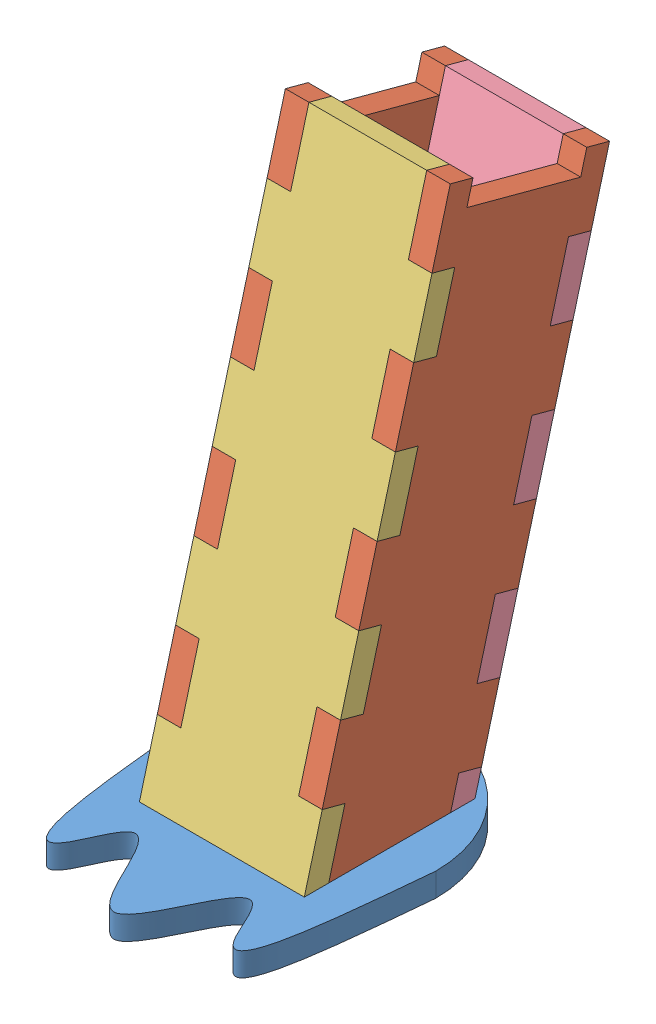
SolidWorks assembly long_leg, configuration Default. Lengths in mm.
Overall size (64 154.05 105.26).
5 component instances, 4 part files, 13 mates.
Components (placement in the parent):
- foot-1: foot [Default] at (14.0978 6 -58.9389) x (1 0 0) z (0 -1 0) size (64 82 6)
- long_leg_right-1: long_leg_right [Default] at (81.114 -18.404 -50.7031) x (0 0.258819 0.965926) z (-1 0 0) size (42 148.23 6)
- long_leg_right-2: long_leg_right [Default] at (45.114 -18.404 -50.7031) x (0 0.258819 0.965926) z (-1 0 0) size (42 148.23 6)
- long_leg_front-1: long_leg_front [Default] at (21.1047 -7.2156 0.7968) x (1 0 0) z (0 0.258819 0.965926) size (42 148.23 6)
- long_leg_back-1: long_leg_back [Default] at (97.9981 -5.6307 -30.6862) x (-1 0 0) z (0 -0.258819 -0.965926) size (42 140.19 6)
Mates (geometry in assembly coordinates):
- Coincident1: coincident anti-aligned: plane of foot-1 through (60.114 0 30.9857) normal (0 -1 0)
- Coincident2: coincident anti-aligned: plane of long_leg_right-2 through (39.114 38.86 -11.5492) normal (0 0.258819 0.965926); plane of long_leg_front-1 through (21.1047 -7.2156 0.7968) normal (0 -0.258819 -0.965926)
- Coincident3: coincident anti-aligned: plane of long_leg_right-2 through (45.114 -18.404 -50.7031) normal (1 0 0); plane of long_leg_front-1 through (45.114 40.4129 -5.7536) normal (-1 0 0)
- Coincident4: coincident anti-aligned: plane of long_leg_right-2 through (39.114 38.86 -11.5492) normal (0 0.965926 -0.258819); plane of long_leg_front-1 through (45.114 40.4129 -5.7536) normal (0 -0.965926 0.258819)
- Coincident5: coincident anti-aligned: plane of long_leg_right-1 through (75.114 0 -1.1367) normal (0 0.258819 0.965926); plane of long_leg_front-1 through (21.1047 -7.2156 0.7968) normal (0 -0.258819 -0.965926)
- Coincident6: coincident anti-aligned: plane of long_leg_right-1 through (75.114 -18.404 -50.7031) normal (-1 0 0); plane of long_leg_front-1 through (75.114 144.7329 -33.7061) normal (1 0 0)
- Coincident7: coincident anti-aligned: plane of long_leg_right-1 through (75.114 127.3463 -29.0473) normal (0 -0.965926 0.258819); plane of long_leg_front-1 through (81.114 127.3463 -29.0473) normal (0 0.965926 -0.258819)
- Coincident8: coincident anti-aligned: plane of long_leg_right-1 through (75.114 13.7088 -35.8682) normal (0 -0.258819 -0.965926); plane of long_leg_back-1 through (97.9981 -5.6307 -30.6862) normal (0 0.258819 0.965926)
- Coincident9: coincident anti-aligned: plane of long_leg_right-1 through (75.114 12.1559 -41.6638) normal (0 -0.965926 0.258819); plane of long_leg_back-1 through (75.114 12.1559 -41.6638) normal (0 0.965926 -0.258819)
- Coincident10: coincident anti-aligned: plane of long_leg_right-1 through (75.114 -18.404 -50.7031) normal (-1 0 0); plane of long_leg_back-1 through (75.114 29.5425 -46.3225) normal (1 0 0)
- Coincident13: coincident anti-aligned: plane of foot-1 through (39.114 0 -58.9389) normal (1 0 0); plane of long_leg_right-2 through (39.114 -18.404 -50.7031) normal (-1 0 0)
- Coincident15: coincident aligned: plane of foot-1 through (60.114 0 30.9857) normal (0 -1 0); plane of long_leg_right-1 through (75.114 0 -32.195) normal (0 -1 0)
- Coincident19: coincident: line of foot-1 through (81.114 6 -40.0143) axis (-1 0 0); plane of long_leg_back-1 through (97.9981 -7.1836 -36.4818) normal (0 -0.258819 -0.965926)
